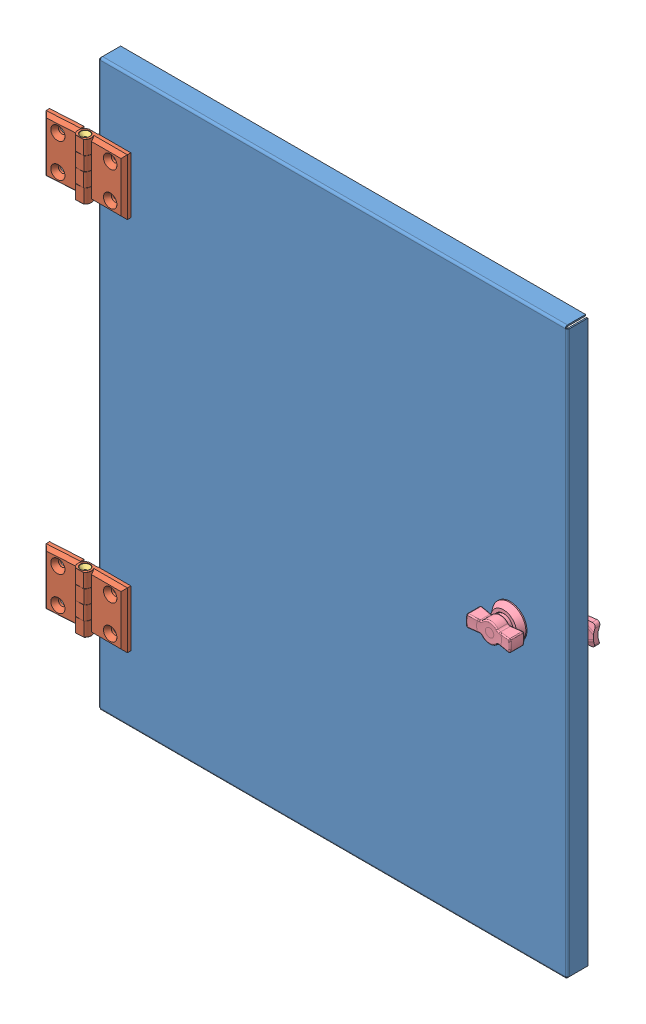
SolidWorks assembly KR.10.11, configuration Default. Lengths in mm.
Overall size (463.8 506 55.38).
10 component instances, 4 part files, 8 mates.
Components (placement in the parent):
- KR.12.18-1: KR.12.18 [Default<Makinelenmiş Olarak>] at (279.0345 246.3434 361.2584) x (-1 0 0) z (0 0 -1) size (420 506 18.2)
- 45x45_MENTESE_ZAMAK-DOGUS-3: 45x45_MENTESE_ZAMAK-DOGUS [Default] at (27.4901 389.0434 364.5645) x (0.998231 0 -0.059447) z (0 -1 0) size (70.79 13.23 50.33)
  - 45x45_MENTESE_ZAMAK-DOGUS-kanat-1: 45x45_MENTESE_ZAMAK-DOGUS-kanat [Default] at origin size (41.25 10.8 50.31)
  - 45x45_MENTESE_ZAMAK-DOGUS-kanat-2: 45x45_MENTESE_ZAMAK-DOGUS-kanat [Default] at (70.7943 2.1061 -50.3) x (-0.998231 -0.059447 0) z (0 0 -1) size (41.25 10.8 50.31)
  - 45x45_MENTESE_ZAMAK-DOGUS-pm-1: 45x45_MENTESE_ZAMAK-DOGUS-pm [Default] at (35.25 5.65 0) x (0.918345 -0.395781 0) z (0 0 1) size (8.53 8.53 50)
- 45x45_MENTESE_ZAMAK-DOGUS-4: 45x45_MENTESE_ZAMAK-DOGUS [Default] at (27.4901 53.3434 364.5645) x (0.998231 0 -0.059447) z (0 -1 0) size (70.79 13.23 50.33)
  - 45x45_MENTESE_ZAMAK-DOGUS-kanat-1: 45x45_MENTESE_ZAMAK-DOGUS-kanat [Default] at origin size (41.25 10.8 50.31)
  - 45x45_MENTESE_ZAMAK-DOGUS-kanat-2: 45x45_MENTESE_ZAMAK-DOGUS-kanat [Default] at (70.7943 2.1061 -50.3) x (-0.998231 -0.059447 0) z (0 0 -1) size (41.25 10.8 50.31)
  - 45x45_MENTESE_ZAMAK-DOGUS-pm-1: 45x45_MENTESE_ZAMAK-DOGUS-pm [Default] at (35.25 5.65 0) x (0.918345 -0.395781 0) z (0 0 1) size (8.53 8.53 50)
- 062-1-1-CC MILLI KILIT-1: 062-1-1-CC MILLI KILIT [Default] at (437.8345 246.3434 368.4584) x (0.999751 -0.022324 0) z (-0.022324 -0.999751 0) size (69.82 55.38 325)
Mates (geometry in assembly coordinates):
- Çakışık5: coincident anti-aligned: plane of KR.12.18-1 through (279.0345 246.3434 362.4584) normal (0 0 1); plane of 45x45_MENTESE_ZAMAK-DOGUS-3/45x45_MENTESE_ZAMAK-DOGUS-kanat-2 through (98.2845 389.0434 362.4584) normal (0 0 -1)
- Eş Merkezli5: concentric aligned: cylinder of KR.12.18-1 through (85.7845 429.3434 352.4584) axis (0 0 1) radius 3.05; cylinder of 45x45_MENTESE_ZAMAK-DOGUS-3/45x45_MENTESE_ZAMAK-DOGUS-kanat-2 through (85.7845 429.3434 368.4584) axis (0 0 1) radius 3.05
- Eş Merkezli6: concentric aligned: cylinder of KR.12.18-1 through (85.7845 399.0434 352.4584) axis (0 0 1) radius 3.05; cylinder of 45x45_MENTESE_ZAMAK-DOGUS-3/45x45_MENTESE_ZAMAK-DOGUS-kanat-2 through (85.7845 399.0434 368.4584) axis (0 0 1) radius 3.05
- Çakışık6: coincident anti-aligned: plane of KR.12.18-1 through (279.0345 246.3434 362.4584) normal (0 0 1); plane of 45x45_MENTESE_ZAMAK-DOGUS-4/45x45_MENTESE_ZAMAK-DOGUS-kanat-2 through (98.2845 53.3434 362.4584) normal (0 0 -1)
- Eş Merkezli7: concentric aligned: cylinder of KR.12.18-1 through (85.7845 93.6434 352.4584) axis (0 0 1) radius 3.05; cylinder of 45x45_MENTESE_ZAMAK-DOGUS-4/45x45_MENTESE_ZAMAK-DOGUS-kanat-2 through (85.7845 93.6434 368.4584) axis (0 0 1) radius 3.05
- Eş Merkezli8: concentric aligned: cylinder of KR.12.18-1 through (85.7845 63.3434 352.4584) axis (0 0 1) radius 3.05; cylinder of 45x45_MENTESE_ZAMAK-DOGUS-4/45x45_MENTESE_ZAMAK-DOGUS-kanat-2 through (85.7845 63.3434 368.4584) axis (0 0 1) radius 3.05
- Çakışık7: coincident anti-aligned: plane of KR.12.18-1 through (279.0345 246.3434 362.4584) normal (0 0 1); plane of 062-1-1-CC MILLI KILIT-1 through (422.7004 262.1688 362.4584) normal (0 0 -1)
- Eş Merkezli9: concentric aligned: cylinder of KR.12.18-1 through (437.8345 246.3434 371.2584) axis (0 0 -1) radius 11.2; cylinder of 062-1-1-CC MILLI KILIT-1 through (437.8345 246.3434 362.4584) axis (0 0 -1) radius 11
